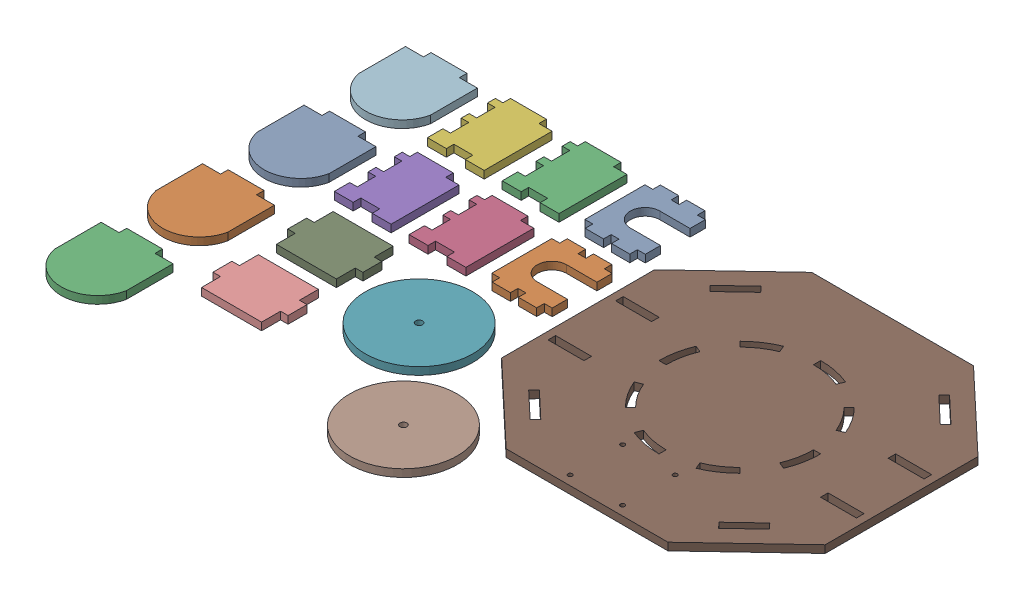
SolidWorks assembly baseForCutting, configuration Default. Lengths in mm.
Overall size (453.14 5.33 280.93).
15 component instances, 6 part files, 42 mates.
Components (placement in the parent):
- backwallV1-1: backwallV1 [Default] at (-158.6994 -68.7981 -96.7313) x (0 0 -1) z (0 -1 0) size (53.09 42.67 5.33)
- backwallV1-2: backwallV1 [Default] at (-158.6994 -68.7981 -30.9453) x (0 0 -1) z (0 -1 0) size (53.09 42.67 5.33)
- sidewallV1-1: sidewallV1 [Default] at (-211.5314 -68.7981 -149.8173) x (1 0 0) z (0 -1 0) size (40.13 53.34 5.33)
- sidewallV1-2: sidewallV1 [Default] at (-211.5314 -68.7981 -84.0313) x (1 0 0) z (0 -1 0) size (40.13 53.34 5.33)
- sidewallV1-3: sidewallV1 [Default] at (-264.3634 -68.7981 -84.0313) x (1 0 0) z (0 -1 0) size (40.13 53.34 5.33)
- sidewallV1-4: sidewallV1 [Default] at (-264.3634 -68.7981 -149.8173) x (1 0 0) z (0 -1 0) size (40.13 53.34 5.33)
- wheel-1: wheel [Default] at (-154.0275 -68.7981 19.7548) x (-0.188379 0 0.982096) z (0 -1 0) size (76 76 5.33)
- wheel-2: wheel [Default] at (-97.0719 -68.7981 87.7531) x (0.152697 0 0.988273) z (0 -1 0) size (76 76 5.33)
- topwallV1-1: topwallV1 [Default] at (-257.8135 -74.1321 22.1407) x (1 0 0) z (0 1 0) size (53.09 40.13 5.33)
- topwallV1-2: topwallV1 [Default] at (-257.8135 -74.1321 74.9727) x (1 0 0) z (0 1 0) size (53.09 40.13 5.33)
- platformV4-1: platformV4 [Default] at (-103.3274 -74.1321 66.0827) size (228.6 5.33 215.9)
- skid-1: skid [Default] at (-289.7424 -74.1321 -51.7273) x (1 0 0) z (0 1 0) size (50.8 58.97 5.33)
- skid-2: skid [Default] at (-289.7424 -74.1321 19.9467) x (1 0 0) z (0 1 0) size (50.8 58.97 5.33)
- skid-3: skid [Default] at (-289.7424 -74.1321 91.6208) x (1 0 0) z (0 1 0) size (50.8 58.97 5.33)
- skid-4: skid [Default] at (-289.7424 -74.1321 163.2948) x (1 0 0) z (0 1 0) size (50.8 58.97 5.33)
Mates (geometry in assembly coordinates):
- Distance3: distance = 12.7 mm anti-aligned: plane of backwallV1-2 through (-158.6994 -74.1321 -84.0313) normal (0 0 -1); plane of backwallV1-1 through (-158.6994 -74.1321 -96.7313) normal (0 0 1)
- Coincident34: coincident aligned: plane of sidewallV1-1 through (-211.5314 -74.1321 -149.8173) normal (0 0 -1); plane of sidewallV1-4 through (-264.3634 -74.1321 -149.8173) normal (0 0 -1)
- Distance8: distance = 12.7 mm anti-aligned: plane of sidewallV1-1 through (-211.5314 -74.1321 -149.8173) normal (-1 0 0); plane of sidewallV1-4 through (-224.2314 -74.1321 -149.8173) normal (1 0 0)
- Coincident31: coincident aligned: plane of sidewallV1-2 through (-211.5314 -74.1321 -84.0313) normal (0 0 -1); plane of sidewallV1-3 through (-264.3634 -74.1321 -84.0313) normal (0 0 -1)
- Distance7: distance = 12.7 mm anti-aligned: plane of sidewallV1-3 through (-224.2314 -74.1321 -84.0313) normal (1 0 0); plane of sidewallV1-2 through (-211.5314 -74.1321 -84.0313) normal (-1 0 0)
- Coincident19: coincident aligned: plane of backwallV1-1 through (-158.6994 -74.1321 -149.8173) normal (0 0 -1); plane of sidewallV1-1 through (-211.5314 -74.1321 -149.8173) normal (0 0 -1)
- Distance5: distance = 12.7 mm anti-aligned: plane of sidewallV1-1 through (-171.3994 -74.1321 -149.8173) normal (1 0 0); plane of backwallV1-1 through (-158.6994 -74.1321 -96.7313) normal (-1 0 0)
- Coincident22: coincident aligned: plane of backwallV1-2 through (-158.6994 -74.1321 -84.0313) normal (0 0 -1); plane of sidewallV1-2 through (-211.5314 -74.1321 -84.0313) normal (0 0 -1)
- Distance6: distance = 12.7 mm anti-aligned: plane of sidewallV1-2 through (-171.3994 -74.1321 -84.0313) normal (1 0 0); plane of backwallV1-2 through (-158.6994 -74.1321 -30.9453) normal (-1 0 0)
- Distance14: distance = 12.7 mm anti-aligned: cylinder of wheel-1 through (-154.0275 -74.1321 19.7548) axis (0 1 0) radius 38.0001; plane of backwallV1-2 through (-158.6994 -74.1321 -30.9453) normal (0 0 1)
- Distance11: distance = 12.7 mm: cylinder of wheel-2 through (-97.0719 -74.1321 87.7531) axis (0 1 0) radius 38.0001; cylinder of wheel-1 through (-154.0275 -74.1321 19.7548) axis (0 1 0) radius 38.0001
- Distance16: distance = 12.7 mm anti-aligned: plane of topwallV1-1 through (-257.8135 -68.7981 -17.9913) normal (0 0 -1); plane of sidewallV1-3 through (-264.3634 -74.1321 -30.6913) normal (0 0 1)
- Distance17: distance = 12.7 mm anti-aligned: plane of topwallV1-1 through (-204.7275 -68.7981 22.1407) normal (1 0 0); cylinder of wheel-1 through (-154.0275 -74.1321 19.7548) axis (0 1 0) radius 38.0001
- Coincident42: coincident aligned: plane of topwallV1-1 through (-252.4795 -74.1321 22.1407) normal (-1 0 0); plane of topwallV1-2 through (-252.4795 -74.1321 74.9727) normal (-1 0 0)
- Distance18: distance = 12.7 mm anti-aligned: plane of topwallV1-2 through (-257.8135 -68.7981 34.8407) normal (0 0 -1); plane of topwallV1-1 through (-257.8135 -68.7981 22.1407) normal (0 0 1)
- Coincident44: coincident aligned: plane of wheel-2 through (-97.0719 -68.7981 87.7531) normal (0 1 0); plane of platformV4-1 through (-103.3274 -68.7981 66.0827) normal (0 1 0)
- Coincident45: coincident aligned: plane of wheel-1 through (-154.0275 -68.7981 19.7548) normal (0 1 0); plane of platformV4-1 through (-103.3274 -68.7981 66.0827) normal (0 1 0)
- Coincident46: coincident aligned: plane of backwallV1-2 through (-158.6994 -68.7981 -30.9453) normal (0 1 0); plane of platformV4-1 through (-103.3274 -68.7981 66.0827) normal (0 1 0)
- Coincident47: coincident aligned: plane of backwallV1-1 through (-158.6994 -68.7981 -96.7313) normal (0 1 0); plane of platformV4-1 through (-103.3274 -68.7981 66.0827) normal (0 1 0)
- Coincident48: coincident aligned: plane of sidewallV1-2 through (-211.5314 -68.7981 -84.0313) normal (0 1 0); plane of platformV4-1 through (-103.3274 -68.7981 66.0827) normal (0 1 0)
- Coincident49: coincident aligned: plane of sidewallV1-1 through (-211.5314 -68.7981 -149.8173) normal (0 1 0); plane of platformV4-1 through (-103.3274 -68.7981 66.0827) normal (0 1 0)
- Coincident50: coincident aligned: plane of topwallV1-2 through (-257.8135 -68.7981 74.9727) normal (0 1 0); plane of platformV4-1 through (-103.3274 -68.7981 66.0827) normal (0 1 0)
- Coincident51: coincident aligned: plane of topwallV1-1 through (-257.8135 -68.7981 22.1407) normal (0 1 0); plane of platformV4-1 through (-103.3274 -68.7981 66.0827) normal (0 1 0)
- Coincident52: coincident aligned: plane of sidewallV1-3 through (-264.3634 -68.7981 -84.0313) normal (0 1 0); plane of platformV4-1 through (-103.3274 -68.7981 66.0827) normal (0 1 0)
- Coincident53: coincident aligned: plane of sidewallV1-4 through (-264.3634 -68.7981 -149.8173) normal (0 1 0); plane of platformV4-1 through (-103.3274 -68.7981 66.0827) normal (0 1 0)
- Distance19: distance = 12.7 mm anti-aligned: plane of platformV4-1 through (-103.3274 -68.7981 66.0827) normal (-1 0 0); plane of backwallV1-2 through (-116.0274 -74.1321 -30.9453) normal (1 0 0)
- Coincident56: coincident aligned: plane of platformV4-1 through (-103.3274 -68.7981 66.0827) normal (0 1 0); plane of skid-1 through (-302.4634 -68.7981 -116.7973) normal (0 1 0)
- Coincident57: coincident aligned: plane of sidewallV1-4 through (-264.3634 -74.1321 -149.8173) normal (0 0 -1); plane of skid-1 through (-327.8634 -68.7981 -149.8173) normal (0 0 -1)
- Distance20: distance = 12.7 mm anti-aligned: plane of skid-1 through (-277.0634 -68.7981 -149.8173) normal (1 0 0); plane of sidewallV1-4 through (-264.3634 -74.1321 -149.8173) normal (-1 0 0)
- Distance21: distance = 12.7 mm anti-aligned: plane of backwallV1-1 through (-116.0274 -74.1321 -96.7313) normal (1 0 0); plane of platformV4-1 through (-103.3274 -68.7981 66.0827) normal (-1 0 0)
- Coincident61: coincident aligned: plane of platformV4-1 through (-103.3274 -68.7981 66.0827) normal (0 1 0); plane of skid-2 through (-302.4634 -68.7981 -45.1233) normal (0 1 0)
- Distance22: distance = 12.7 mm anti-aligned: plane of skid-2 through (-277.0634 -68.7981 -78.1433) normal (1 0 0); plane of sidewallV1-3 through (-264.3634 -74.1321 -84.0313) normal (-1 0 0)
- Distance23: distance = 12.7 mm anti-aligned: plane of skid-2 through (-327.8634 -68.7981 -78.1433) normal (0 0 -1); cylinder of skid-1 through (-302.4634 -68.7981 -116.7973) axis (0 -1 0) radius 25.954
- Distance24: distance = 12.7 mm anti-aligned: cylinder of wheel-1 through (-154.0275 -74.1321 19.7548) axis (0 1 0) radius 38.0001; plane of platformV4-1 through (-103.3274 -68.7981 66.0827) normal (-1 0 0)
- Coincident64: coincident aligned: plane of backwallV1-1 through (-158.6994 -74.1321 -149.8173) normal (0 0 -1); plane of platformV4-1 through (-103.3274 -68.7981 -149.8173) normal (0 0 -1)
- Coincident65: coincident aligned: plane of platformV4-1 through (-103.3274 -68.7981 66.0827) normal (0 1 0); plane of skid-3 through (-302.4634 -68.7981 26.5508) normal (0 1 0)
- Distance25: distance = 12.7 mm anti-aligned: plane of skid-3 through (-327.8634 -68.7981 -6.4692) normal (0 0 -1); cylinder of skid-2 through (-302.4634 -68.7981 -45.1233) axis (0 -1 0) radius 25.954
- Coincident66: coincident aligned: plane of skid-2 through (-277.0634 -68.7981 -78.1433) normal (1 0 0); plane of skid-3 through (-277.0634 -68.7981 -6.4692) normal (1 0 0)
- Coincident67: coincident aligned: plane of platformV4-1 through (-103.3274 -68.7981 66.0827) normal (0 1 0); plane of skid-4 through (-302.4634 -68.7981 98.2248) normal (0 1 0)
- Distance26: distance = 12.7 mm anti-aligned: plane of skid-4 through (-327.8634 -68.7981 65.2048) normal (0 0 -1); cylinder of skid-3 through (-302.4634 -68.7981 26.5508) axis (0 -1 0) radius 25.954
- Coincident68: coincident aligned: plane of skid-3 through (-277.0634 -68.7981 -6.4692) normal (1 0 0); plane of skid-4 through (-277.0634 -68.7981 65.2048) normal (1 0 0)
- Distance27: distance = 12.7 mm anti-aligned: cylinder of wheel-2 through (-97.0719 -74.1321 87.7531) axis (0 1 0) radius 38.0001; plane of platformV4-1 through (-103.3274 -74.1321 12.1077) normal (-0.686624 0 0.727013)
